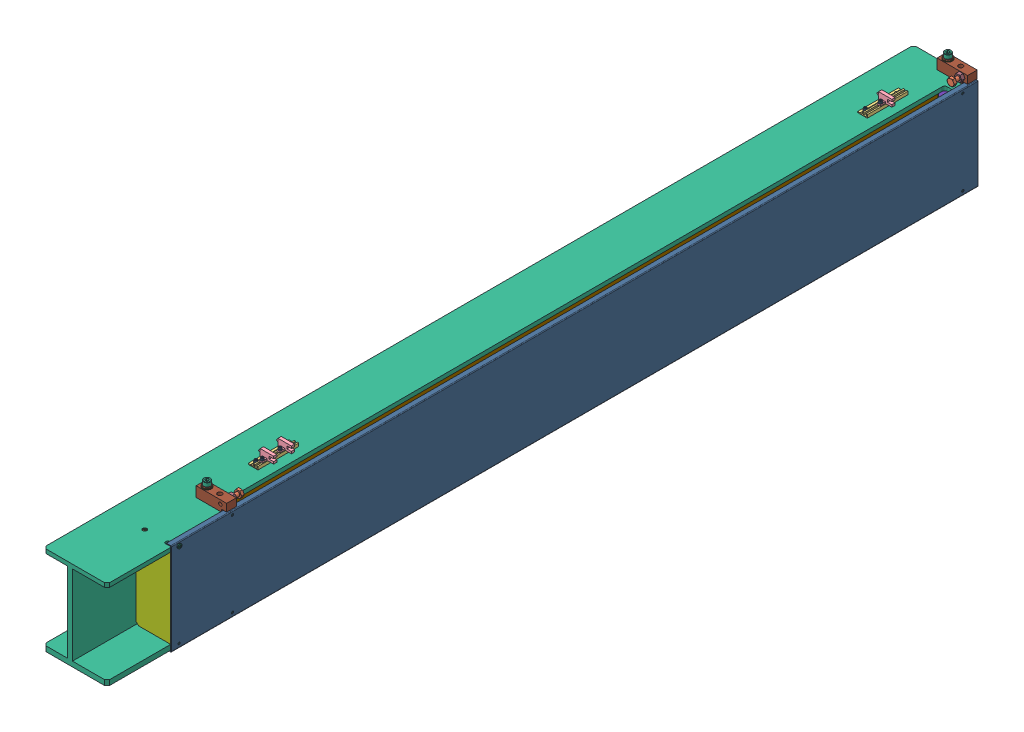
SolidWorks assembly _0227_SA03, configuration Default. Lengths in mm.
Overall size (128.98 209.6 1710.78).
64 component instances, 28 part files, 168 mates.
Components (placement in the parent):
- 0227_003_MS5-10-1: 0227_003_MS5-10 [Default] at (-74.5 -50 -288) x (-1 0 0) z (0 -0.924225 -0.381849) size (10 5.08 5.24)
- 0227_003_MS5-10-2: 0227_003_MS5-10 [Default] at (-74.5 -156 -288) x (-1 0 0) z (0 -0.924225 -0.381849) size (10 5.08 5.24)
- 0227_003_MS5-10-3: 0227_003_MS5-10 [Default] at (-74.5 -50 -1668) x (-1 0 0) z (0 -0.924225 -0.381849) size (10 5.08 5.24)
- 0227_003_MS5-10-4: 0227_003_MS5-10 [Default] at (-74.5 -156 -1668) x (-1 0 0) z (0 -0.924225 -0.381849) size (10 5.08 5.24)
- 0227_010_STRN8-30-1: 0227_010_STRN8-30 [Default] at (-12.5 12.5 -269.5) x (0 0 1) z (0 -1 0) size (35.5 15 13)
- 0227_010_STRN8-30-2: 0227_010_STRN8-30 [Default] at (-12.5 12.5 -1675.5) x (0 0 -1) z (0 -1 0) size (35.5 15 13)
- 0227_011_SENCF3-80-1: 0227_011_SENCF3-80 [Default] at (-46 0 -422.5) x (0 1 0) z (0 0 -1) size (6 19 80)
- 0227_011_SENCF3-80-2: 0227_011_SENCF3-80 [Default] at (-46 0 -1620) x (0 1 0) z (0 0 -1) size (6 19 80)
- 0227_012_FPMT44-1: 0227_012_FPMT44 [Default] at (-60.8 12.7 -361.8) x (0 1 0) z (-1 0 0) size (13.4 26 31.2)
- 0227_012_FPMT44-2: 0227_012_FPMT44 [Default] at (-60.8 12.7 -1576.8) x (0 1 0) z (-1 0 0) size (13.4 26 31.2)
- 0227_012_FPMT44-3: 0227_012_FPMT44 [Default] at (-60.8 12.7 -396.8) x (0 1 0) z (-1 0 0) size (13.4 26 31.2)
- 0227_013_MS6-15-1: 0227_013_MS6-15 [Default] at (-74.5 -50 -195) x (-1 0 0) z (0 -0.594861 -0.803828) size (15 6.1 6.29)
- 0227_013_MS6-15-2: 0227_013_MS6-15 [Default] at (-74.5 -140 -195) x (-1 0 0) z (0 -0.52179 0.853074) size (15 6.1 6.29)
- 0227_201_Base-1: 0227_201_Base [Default] at origin size (125 175 1710)
- 0227_202_Rib-1: 0227_202_Rib [Default] at (-68 -86.5 -125) size (68 157 10)
- 0227_203_Rib-1: 0227_203_Rib [Default] at (-68 -86.5 -1702) size (68 157 8)
- 0227_205_Spacer-1: 0227_205_Spacer [Default] at (-68 -47.5 -260) size (23.5 19 1420)
- 0227_205_Spacer-2: 0227_205_Spacer [Default] at (-68 -153.5 -260) size (23.5 19 1420)
- 0227_207_Cover-1: 0227_207_Cover [Default] at (1.5 3 -125) size (10 181 1585)
- 0227_213_Block-1: 0227_213_Block [Default] at (-60 0 -244.5) size (60 20 19)
- 0227_213_Block-2: 0227_213_Block [Default] at (-60 0 -1700.5) size (60 20 19)
- 0227_309_SCB4-15-1: 0227_309_SCB4-15 [Default] at (-56 -4.5 -130) x (0 -1 0) z (0.5 0 0.866025) size (19 7 7)
- 0227_309_SCB4-15-2: 0227_309_SCB4-15 [Default] at (-56 -170.5 -130) x (0 1 0) z (-0.5 0 0.866025) size (19 7 7)
- 0227_309_SCB4-15-3: 0227_309_SCB4-15 [Default] at (-56 -170.5 -1706) x (0 1 0) z (-0.5 0 0.866025) size (19 7 7)
- 0227_309_SCB4-15-4: 0227_309_SCB4-15 [Default] at (-56 -4.5 -1706) x (0 -1 0) z (0.5 0 0.866025) size (19 7 7)
- 0227_313_SHNJ-M8-1: 0227_313_SHNJ-M8 [Default] at (-12.5 12.5 -260.5) x (0 0 1) z (-0.866025 -0.5 0) size (6.5 15.01 13)
- 0227_313_SHNJ-M8-2: 0227_313_SHNJ-M8 [Default] at (-12.5 12.5 -1684.5) x (0 0 -1) z (0.866025 -0.5 0) size (6.5 15.01 13)
- 0227_314_SHNJ-M3-1: 0227_314_SHNJ-M3 [Default] at (-50.5 2.1 -355.5) x (1 0 0) z (0 -1 0) size (5.5 6.35 2.4)
- 0227_314_SHNJ-M3-2: 0227_314_SHNJ-M3 [Default] at (-50.5 2.1 -390.5) x (1 0 0) z (0 -1 0) size (5.5 6.35 2.4)
- 0227_314_SHNJ-M3-3: 0227_314_SHNJ-M3 [Default] at (-50.5 2.1 -1570.5) x (1 0 0) z (0 -1 0) size (5.5 6.35 2.4)
- 0227_315_BDJS4-8-1: 0227_315_BDJS4-8 [Default] at (1.5 -4 -140) x (-1 0 0) z (0 0 -1) size (10.48 8.3 8.3)
- 0227_317_PWF8-1: 0227_317_PWF8 [Default] at (-48 20.8 -244.5) x (0 -1 0) z (-0.246577 0 0.969123) size (1.6 17 17)
- 0227_317_PWF8-2: 0227_317_PWF8 [Default] at (-48 20.8 -1700.5) x (0 -1 0) z (0 0 1) size (1.6 17 17)
- 0227_318_PWF5-1: 0227_318_PWF5 [Default] at (-78.5 -28 -130) size (1 10 10)
- 0227_319_PWF4-1: 0227_319_PWF4 [Default] at (-78.4 -143 -288) size (0.8 9 9)
- 0227_319_PWF4-2: 0227_319_PWF4 [Default] at (-78.4 -37 -288) size (0.8 9 9)
- 0227_319_PWF4-3: 0227_319_PWF4 [Default] at (-78.4 -28 -1706) size (0.8 9 9)
- 0227_320_PWF3-1: 0227_320_PWF3 [Default] at (-60 2.25 -352.5) x (0 -1 0) z (0 0 1) size (0.5 7 7)
- 0227_320_PWF3-2: 0227_320_PWF3 [Default] at (-50.5 9.25 -355.5) x (0 -1 0) z (0 0 1) size (0.5 7 7)
- 0227_320_PWF3-3: 0227_320_PWF3 [Default] at (-60 2.25 -1550) x (0 -1 0) z (0 0 1) size (0.5 7 7)
- 0227_320_PWF3-4: 0227_320_PWF3 [Default] at (-50.5 9.25 -390.5) x (0 -1 0) z (0 0 1) size (0.5 7 7)
- 0227_320_PWF3-5: 0227_320_PWF3 [Default] at (-50.5 9.25 -1570.5) x (0 -1 0) z (0 0 1) size (0.5 7 7)
- 0227_321_SLW8-1: 0227_321_SLW8 [Default] at (-48 22.6 -244.5) x (0 -1 0) z (1 0 0) size (2 15.4 15.4)
- 0227_321_SLW8-2: 0227_321_SLW8 [Default] at (-48 22.6 -1700.5) x (0 -1 0) z (1 0 0) size (2 15.4 15.4)
- 0227_322_SLW5-1: 0227_322_SLW5 [Default] at (-79.65 -28 -130) x (1 0 0) z (0 1 0) size (1.3 9.2 9.2)
- 0227_323_SLW4-1: 0227_323_SLW4 [Default] at (-79.3 -143 -288) x (1 0 0) z (0 -1 0) size (1 7.6 7.6)
- 0227_323_SLW4-2: 0227_323_SLW4 [Default] at (-79.3 -37 -288) x (1 0 0) z (0 -1 0) size (1 7.6 7.6)
- 0227_323_SLW4-3: 0227_323_SLW4 [Default] at (-79.3 -28 -1706) x (1 0 0) z (0 -1 0) size (1 7.6 7.6)
- 0227_324_SLW3-1: 0227_324_SLW3 [Default] at (-60 2.85 -352.5) x (0 -1 0) z (1 0 0) size (0.7 5.9 5.9)
- 0227_324_SLW3-2: 0227_324_SLW3 [Default] at (-50.5 9.85 -355.5) x (0 -1 0) z (0.999786 0 0.020691) size (0.7 5.9 5.9)
- 0227_324_SLW3-3: 0227_324_SLW3 [Default] at (-60 2.85 -1550) x (0 -1 0) z (1 0 0) size (0.7 5.9 5.9)
- 0227_324_SLW3-4: 0227_324_SLW3 [Default] at (-50.5 9.85 -390.5) x (0 -1 0) z (1 0 0) size (0.7 5.9 5.9)
- 0227_324_SLW3-5: 0227_324_SLW3 [Default] at (-50.5 9.85 -1570.5) x (0 -1 0) z (1 0 0) size (0.7 5.9 5.9)
- 0227_301_SCB8-30-1: 0227_301_SCB8-30 [Default] at (-48 23.6 -244.5) x (0 -1 0) z (-0.5 0 -0.866025) size (38 13 13)
- 0227_301_SCB8-30-2: 0227_301_SCB8-30 [Default] at (-48 23.6 -1700.5) x (0 -1 0) z (-0.5 0 -0.866025) size (38 13 13)
- 0227_304_SCB5-20-1: 0227_304_SCB5-20 [Default] at (-80.3 -28 -130) x (1 0 0) z (0 -0.5 0.866025) size (25 8.5 8.5)
- 0227_308_SCB4-16-1: 0227_308_SCB4-16 [Default] at (-79.8 -143 -288) x (1 0 0) z (0 0.5 0.866025) size (20 7 7)
- 0227_307_SCB4-20-1: 0227_307_SCB4-20 [Default] at (-79.8 -37 -288) x (1 0 0) z (0 0.5 0.866025) size (24 7 7)
- 0227_307_SCB4-20-2: 0227_307_SCB4-20 [Default] at (-79.8 -28 -1706) x (1 0 0) z (0 0.5 0.866025) size (24 7 7)
- 0227_311_SCB3-8-1: 0227_311_SCB3-8 [Default] at (-60 3.2 -352.5) x (0 -1 0) z (-0.5 0 0.866025) size (11 5.5 5.5)
- 0227_311_SCB3-8-2: 0227_311_SCB3-8 [Default] at (-50.5 10.2 -355.5) x (0 -1 0) z (-0.5 0 0.866025) size (11 5.5 5.5)
- 0227_311_SCB3-8-3: 0227_311_SCB3-8 [Default] at (-60 3.2 -1550) x (0 -1 0) z (-0.5 0 0.866025) size (11 5.5 5.5)
- 0227_311_SCB3-8-4: 0227_311_SCB3-8 [Default] at (-50.5 10.2 -390.5) x (0 -1 0) z (-0.5 0 0.866025) size (11 5.5 5.5)
- 0227_311_SCB3-8-5: 0227_311_SCB3-8 [Default] at (-50.5 10.2 -1570.5) x (0 -1 0) z (-0.5 0 0.866025) size (11 5.5 5.5)
Mates (geometry in assembly coordinates):
- Concentric1: concentric aligned: cylinder of 0227_201_Base-1 through (-78 -28 -130) axis (-1 0 0) radius 2.75; cylinder of 0227_202_Rib-1 through (-68 -28 -130) axis (-1 0 0) radius 2.1
- Concentric2: concentric aligned: cylinder of 0227_201_Base-1 through (-78 -145 -130) axis (-1 0 0) radius 2.75; cylinder of 0227_202_Rib-1 through (-68 -145 -130) axis (-1 0 0) radius 2.1
- Coincident1: coincident anti-aligned: plane of 0227_201_Base-1 through (-68 -165 0) normal (1 0 0); plane of 0227_202_Rib-1 through (-68 -165 -135) normal (-1 0 0)
- Concentric3: concentric aligned: cylinder of 0227_201_Base-1 through (-78 -145 -1706) axis (-1 0 0) radius 2.25; cylinder of 0227_203_Rib-1 through (-68 -145 -1706) axis (-1 0 0) radius 1.65
- Concentric4: concentric aligned: cylinder of 0227_201_Base-1 through (-78 -86.5 -1706) axis (-1 0 0) radius 2.25; cylinder of 0227_203_Rib-1 through (-68 -86.5 -1706) axis (-1 0 0) radius 1.65
- Coincident2: coincident anti-aligned: plane of 0227_201_Base-1 through (-68 -165 0) normal (1 0 0); plane of 0227_203_Rib-1 through (-68 -165 -1710) normal (-1 0 0)
- Concentric5: concentric anti-aligned: cylinder of 0227_201_Base-1 through (-68 -37 -288) axis (1 0 0) radius 2.25; cylinder of 0227_205_Spacer-1 through (-68 -37 -288) axis (-1 0 0) radius 1.65
- Concentric6: concentric anti-aligned: cylinder of 0227_201_Base-1 through (-68 -37 -468) axis (1 0 0) radius 2.25; cylinder of 0227_205_Spacer-1 through (-68 -37 -468) axis (-1 0 0) radius 1.65
- Concentric7: concentric anti-aligned: cylinder of 0227_201_Base-1 through (-68 -37 -1668) axis (1 0 0) radius 2.25; cylinder of 0227_205_Spacer-1 through (-68 -37 -1668) axis (-1 0 0) radius 1.65
- Concentric8: concentric anti-aligned: cylinder of 0227_201_Base-1 through (-68 -143 -288) axis (1 0 0) radius 2.25; cylinder of 0227_205_Spacer-2 through (-68 -143 -288) axis (-1 0 0) radius 1.65
- Concentric9: concentric anti-aligned: cylinder of 0227_201_Base-1 through (-68 -143 -348) axis (1 0 0) radius 2.25; cylinder of 0227_205_Spacer-2 through (-68 -143 -348) axis (-1 0 0) radius 1.65
- Coincident3: coincident anti-aligned: plane of 0227_201_Base-1 through (-68 -165 0) normal (1 0 0); plane of 0227_205_Spacer-1 through (-68 -28.5 -260) normal (-1 0 0)
- Coincident4: coincident anti-aligned: plane of 0227_201_Base-1 through (-68 -165 0) normal (1 0 0); plane of 0227_205_Spacer-2 through (-68 -134.5 -260) normal (-1 0 0)
- Concentric10: concentric aligned: cylinder of 0227_201_Base-1 through (0 -4 -140) axis (1 0 0) radius 1.65; cylinder of 0227_207_Cover-1 through (1.5 -4 -140) axis (1 0 0) radius 2.25
- Concentric11: concentric aligned: cylinder of 0227_201_Base-1 through (0 -4 -245) axis (1 0 0) radius 1.65; cylinder of 0227_207_Cover-1 through (1.5 -4 -245) axis (1 0 0) radius 2.25
- Coincident6: coincident anti-aligned: plane of 0227_201_Base-1 through (0 -8 0) normal (1 0 0); plane of 0227_207_Cover-1 through (0 -176.5 -1710) normal (-1 0 0)
- Concentric12: concentric aligned: cylinder of 0227_201_Base-1 through (-48 0 -244.5) axis (0 1 0) radius 3.4; cylinder of 0227_213_Block-1 through (-48 20 -244.5) axis (0 1 0) radius 4.5
- Concentric13: concentric aligned: cylinder of 0227_201_Base-1 through (-23 0 -244.5) axis (0 1 0) radius 3.4; cylinder of 0227_213_Block-1 through (-23 20 -244.5) axis (0 1 0) radius 4.5
- Coincident7: coincident anti-aligned: plane of 0227_201_Base-1 through (-125 0 -1710) normal (0 1 0); plane of 0227_213_Block-1 through (-60 0 -254) normal (0 -1 0)
- Concentric14: concentric aligned: cylinder of 0227_201_Base-1 through (-48 0 -1700.5) axis (0 1 0) radius 3.4; cylinder of 0227_213_Block-2 through (-48 20 -1700.5) axis (0 1 0) radius 4.5
- Concentric15: concentric aligned: cylinder of 0227_201_Base-1 through (-23 0 -1700.5) axis (0 1 0) radius 3.4; cylinder of 0227_213_Block-2 through (-23 20 -1700.5) axis (0 1 0) radius 4.5
- Coincident8: coincident anti-aligned: plane of 0227_201_Base-1 through (-125 0 -1710) normal (0 1 0); plane of 0227_213_Block-2 through (-60 0 -1710) normal (0 -1 0)
- Concentric16: concentric aligned: cylinder of 0227_213_Block-1 through (-12.5 12.5 -235) axis (0 0 1) radius 3.4; cylinder of 0227_010_STRN8-30-1 through (-12.5 12.5 -254.6835) axis (0 0 1) radius 4
- Distance1: distance = 15.5 mm anti-aligned: plane of 0227_010_STRN8-30-1 through (-18.45 12.5 -269.5) normal (0 0 1); plane of 0227_213_Block-1 through (-60 20 -254) normal (0 0 -1)
- Parallel1: parallel aligned: plane of 0227_213_Block-1 through (-60 20 -254) normal (0 1 0); plane of 0227_010_STRN8-30-1 through (-16.2528 19 -269.5) normal (0 1 0)
- Concentric17: concentric anti-aligned: cylinder of 0227_213_Block-2 through (-12.5 12.5 -1691) axis (0 0 1) radius 3.4; cylinder of 0227_010_STRN8-30-2 through (-12.5 12.5 -1690.3165) axis (0 0 -1) radius 4
- Distance2: distance = 15.5 mm anti-aligned: plane of 0227_213_Block-2 through (-60 20 -1691) normal (0 0 1); plane of 0227_010_STRN8-30-2 through (-6.55 12.5 -1675.5) normal (0 0 -1)
- Parallel2: parallel aligned: plane of 0227_213_Block-2 through (-60 20 -1710) normal (0 1 0); plane of 0227_010_STRN8-30-2 through (-8.7472 19 -1675.5) normal (0 1 0)
- Concentric18: concentric anti-aligned: cylinder of 0227_201_Base-1 through (-60 0 -352.5) axis (0 1 0) radius 1.25; cylinder of 0227_011_SENCF3-80-1 through (-60 0 -352.5) axis (0 -1 0) radius 1.75
- Concentric19: concentric anti-aligned: cylinder of 0227_201_Base-1 through (-60 0 -412.5) axis (0 1 0) radius 1.25; cylinder of 0227_011_SENCF3-80-1 through (-60 0 -412.5) axis (0 -1 0) radius 1.75
- Coincident13: coincident anti-aligned: plane of 0227_201_Base-1 through (-125 0 -1710) normal (0 1 0); plane of 0227_011_SENCF3-80-1 through (-46 0 -342.5) normal (0 -1 0)
- Concentric20: concentric anti-aligned: cylinder of 0227_201_Base-1 through (-60 0 -1550) axis (0 1 0) radius 1.25; cylinder of 0227_011_SENCF3-80-2 through (-60 0 -1550) axis (0 -1 0) radius 1.75
- Concentric21: concentric anti-aligned: cylinder of 0227_201_Base-1 through (-60 0 -1610) axis (0 1 0) radius 1.25; cylinder of 0227_011_SENCF3-80-2 through (-60 0 -1610) axis (0 -1 0) radius 1.75
- Coincident14: coincident anti-aligned: plane of 0227_201_Base-1 through (-125 0 -1710) normal (0 1 0); plane of 0227_011_SENCF3-80-2 through (-46 0 -1540) normal (0 -1 0)
- Width1: width aligned: plane of 0227_012_FPMT44-1 through (-47.4 9 -378) normal (1 0 0); plane of 0227_012_FPMT44-1 through (-53.6 9 -378) normal (-1 0 0); plane of 0227_011_SENCF3-80-1 through (-46 6 -342.5) normal (1 0 0); plane of 0227_011_SENCF3-80-1 through (-55 2 -342.5) normal (-1 0 0)
- Coincident15: coincident anti-aligned: plane of 0227_011_SENCF3-80-1 through (-48.8 6 -342.5) normal (0 1 0); plane of 0227_012_FPMT44-1 through (-60.8 6 -368.2) normal (0 -1 0)
- Distance3: distance = 9.5 mm aligned: plane of 0227_012_FPMT44-1 through (-47.4 9 -352) normal (0 0 1); plane of 0227_011_SENCF3-80-1 through (-48.8 6 -342.5) normal (0 0 1)
- Coincident17: coincident aligned: plane of 0227_012_FPMT44-1 through (-47.4 9 -378) normal (1 0 0); plane of 0227_012_FPMT44-2 through (-47.4 9 -1593) normal (1 0 0)
- Coincident18: coincident anti-aligned: plane of 0227_011_SENCF3-80-2 through (-48.8 6 -1540) normal (0 1 0); plane of 0227_012_FPMT44-2 through (-60.8 6 -1583.2) normal (0 -1 0)
- Distance4: distance = 27 mm aligned: plane of 0227_012_FPMT44-2 through (-47.4 9 -1567) normal (0 0 1); plane of 0227_011_SENCF3-80-2 through (-48.8 6 -1540) normal (0 0 1)
- Coincident20: coincident aligned: plane of 0227_012_FPMT44-1 through (-47.4 9 -378) normal (1 0 0); plane of 0227_012_FPMT44-3 through (-47.4 9 -413) normal (1 0 0)
- Coincident21: coincident anti-aligned: plane of 0227_011_SENCF3-80-1 through (-48.8 6 -342.5) normal (0 1 0); plane of 0227_012_FPMT44-3 through (-60.8 6 -403.2) normal (0 -1 0)
- Distance5: distance = 9 mm anti-aligned: plane of 0227_012_FPMT44-1 through (-47.4 9 -378) normal (0 0 -1); plane of 0227_012_FPMT44-3 through (-47.4 9 -387) normal (0 0 1)
- Concentric22: concentric anti-aligned: cylinder of 0227_213_Block-1 through (-48 20 -244.5) axis (0 1 0) radius 4.5; cylinder of 0227_317_PWF8-1 through (-48 20.8 -244.5) axis (0 -1 0) radius 4.2
- Coincident23: coincident anti-aligned: plane of 0227_213_Block-1 through (-60 20 -254) normal (0 1 0); plane of 0227_317_PWF8-1 through (-41.8461 20 -242.9342) normal (0 -1 0)
- Concentric23: concentric aligned: cylinder of 0227_213_Block-1 through (-48 20 -244.5) axis (0 1 0) radius 4.5; cylinder of 0227_301_SCB8-30-1 through (-48 -6.4 -244.5) axis (0 1 0) radius 4
- Parallel3: parallel aligned: plane of 0227_213_Block-1 through (0 0 -254) normal (1 0 0); plane of 0227_301_SCB8-30-1 through (-51 27.6 -242.7679) normal (1 0 0)
- Concentric24: concentric anti-aligned: cylinder of 0227_301_SCB8-30-2 through (-48 -6.4 -1700.5) axis (0 1 0) radius 4; cylinder of 0227_317_PWF8-2 through (-48 20.8 -1700.5) axis (0 -1 0) radius 4.2
- Concentric25: concentric aligned: cylinder of 0227_213_Block-2 through (-48 20 -1700.5) axis (0 1 0) radius 4.5; cylinder of 0227_301_SCB8-30-2 through (-48 -6.4 -1700.5) axis (0 1 0) radius 4
- Coincident27: coincident anti-aligned: plane of 0227_213_Block-2 through (-60 20 -1710) normal (0 1 0); plane of 0227_317_PWF8-2 through (-41.65 20 -1700.5) normal (0 -1 0)
- Concentric26: concentric anti-aligned: cylinder of 0227_304_SCB5-20-1 through (-60.3 -28 -130) axis (-1 0 0) radius 2.5; cylinder of 0227_318_PWF5-1 through (-78.5 -28 -130) axis (1 0 0) radius 2.65
- Concentric27: concentric anti-aligned: cylinder of 0227_304_SCB5-20-1 through (-60.3 -28 -130) axis (-1 0 0) radius 2.5; cylinder of 0227_322_SLW5-1 through (-79.65 -28 -130) axis (1 0 0) radius 2.55
- Coincident28: coincident anti-aligned: plane of 0227_304_SCB5-20-1 through (-80.3 -24.3194 -127.875) normal (1 0 0); plane of 0227_322_SLW5-1 through (-80.3 -28 -133.575) normal (-1 0 0)
- Coincident29: coincident anti-aligned: plane of 0227_322_SLW5-1 through (-79 -28 -133.575) normal (1 0 0); plane of 0227_318_PWF5-1 through (-79 -24.175 -130) normal (-1 0 0)
- Concentric28: concentric aligned: cylinder of 0227_201_Base-1 through (-78 -28 -130) axis (-1 0 0) radius 2.75; cylinder of 0227_304_SCB5-20-1 through (-60.3 -28 -130) axis (-1 0 0) radius 2.5
- Coincident30: coincident anti-aligned: plane of 0227_201_Base-1 through (-78 -165 0) normal (-1 0 0); plane of 0227_318_PWF5-1 through (-78 -24.175 -130) normal (1 0 0)
- Parallel4: parallel anti-aligned: plane of 0227_201_Base-1 through (-125 0 -1710) normal (0 1 0); plane of 0227_304_SCB5-20-1 through (-82.8 -26 -131.1547) normal (0 -1 0)
- Perpendicular1: perpendicular: plane of 0227_201_Base-1 through (-125 0 -1710) normal (0 1 0); plane of 0227_322_SLW5-1 through (-79.65 -28 -130) normal (0 0 -1)
- Concentric29: concentric anti-aligned: cylinder of 0227_308_SCB4-16-1 through (-63.8 -143 -288) axis (-1 0 0) radius 2; cylinder of 0227_323_SLW4-1 through (-79.3 -143 -288) axis (1 0 0) radius 2.05
- Concentric30: concentric anti-aligned: cylinder of 0227_308_SCB4-16-1 through (-63.8 -143 -288) axis (-1 0 0) radius 2; cylinder of 0227_319_PWF4-1 through (-78.4 -143 -288) axis (1 0 0) radius 2.15
- Coincident33: coincident anti-aligned: plane of 0227_319_PWF4-1 through (-78.8 -139.675 -288) normal (-1 0 0); plane of 0227_323_SLW4-1 through (-78.8 -143 -285.075) normal (1 0 0)
- Coincident34: coincident anti-aligned: plane of 0227_308_SCB4-16-1 through (-79.8 -139.9689 -289.75) normal (1 0 0); plane of 0227_323_SLW4-1 through (-79.8 -143 -285.075) normal (-1 0 0)
- Concentric31: concentric anti-aligned: cylinder of 0227_308_SCB4-16-1 through (-63.8 -143 -288) axis (-1 0 0) radius 2; cylinder of 0227_201_Base-1 through (-68 -143 -288) axis (1 0 0) radius 2.25
- Coincident35: coincident anti-aligned: plane of 0227_201_Base-1 through (-78 -165 0) normal (-1 0 0); plane of 0227_319_PWF4-1 through (-78 -139.675 -288) normal (1 0 0)
- Parallel5: parallel aligned: plane of 0227_201_Base-1 through (-125 -175 -1710) normal (0 -1 0); plane of 0227_308_SCB4-16-1 through (-81.8 -141.5 -288.866) normal (0 -1 0)
- Parallel6: parallel aligned: plane of 0227_201_Base-1 through (-125 -175 -1710) normal (0 -1 0); plane of 0227_323_SLW4-1 through (-79.3 -143 -288) normal (0 -1 0)
- Concentric32: concentric anti-aligned: cylinder of 0227_307_SCB4-20-1 through (-59.8 -37 -288) axis (-1 0 0) radius 2; cylinder of 0227_323_SLW4-2 through (-79.3 -37 -288) axis (1 0 0) radius 2.05
- Concentric33: concentric anti-aligned: cylinder of 0227_307_SCB4-20-1 through (-59.8 -37 -288) axis (-1 0 0) radius 2; cylinder of 0227_319_PWF4-2 through (-78.4 -37 -288) axis (1 0 0) radius 2.15
- Coincident38: coincident anti-aligned: plane of 0227_323_SLW4-2 through (-78.8 -37 -285.075) normal (1 0 0); plane of 0227_319_PWF4-2 through (-78.8 -33.675 -288) normal (-1 0 0)
- Coincident39: coincident anti-aligned: plane of 0227_307_SCB4-20-1 through (-79.8 -33.9689 -289.75) normal (1 0 0); plane of 0227_323_SLW4-2 through (-79.8 -37 -285.075) normal (-1 0 0)
- Concentric34: concentric anti-aligned: cylinder of 0227_201_Base-1 through (-68 -37 -288) axis (1 0 0) radius 2.25; cylinder of 0227_307_SCB4-20-1 through (-59.8 -37 -288) axis (-1 0 0) radius 2
- Coincident40: coincident anti-aligned: plane of 0227_201_Base-1 through (-78 -165 0) normal (-1 0 0); plane of 0227_319_PWF4-2 through (-78 -33.675 -288) normal (1 0 0)
- Parallel7: parallel aligned: plane of 0227_201_Base-1 through (-125 -8 -1710) normal (0 -1 0); plane of 0227_307_SCB4-20-1 through (-81.8 -35.5 -288.866) normal (0 -1 0)
- Concentric35: concentric anti-aligned: cylinder of 0227_307_SCB4-20-2 through (-59.8 -28 -1706) axis (-1 0 0) radius 2; cylinder of 0227_323_SLW4-3 through (-79.3 -28 -1706) axis (1 0 0) radius 2.05
- Concentric36: concentric anti-aligned: cylinder of 0227_307_SCB4-20-2 through (-59.8 -28 -1706) axis (-1 0 0) radius 2; cylinder of 0227_319_PWF4-3 through (-78.4 -28 -1706) axis (1 0 0) radius 2.15
- Coincident42: coincident anti-aligned: plane of 0227_323_SLW4-3 through (-78.8 -28 -1703.075) normal (1 0 0); plane of 0227_319_PWF4-3 through (-78.8 -24.675 -1706) normal (-1 0 0)
- Coincident43: coincident anti-aligned: plane of 0227_307_SCB4-20-2 through (-79.8 -24.9689 -1707.75) normal (1 0 0); plane of 0227_323_SLW4-3 through (-79.8 -28 -1703.075) normal (-1 0 0)
- Concentric37: concentric aligned: cylinder of 0227_201_Base-1 through (-78 -28 -1706) axis (-1 0 0) radius 2.25; cylinder of 0227_307_SCB4-20-2 through (-59.8 -28 -1706) axis (-1 0 0) radius 2
- Coincident44: coincident anti-aligned: plane of 0227_201_Base-1 through (-78 -165 0) normal (-1 0 0); plane of 0227_319_PWF4-3 through (-78 -24.675 -1706) normal (1 0 0)
- Parallel8: parallel aligned: plane of 0227_201_Base-1 through (-125 -8 -1710) normal (0 -1 0); plane of 0227_307_SCB4-20-2 through (-81.8 -26.5 -1706.866) normal (0 -1 0)
- Parallel9: parallel anti-aligned: plane of 0227_201_Base-1 through (-125 -8 -1710) normal (0 0 -1); plane of 0227_323_SLW4-3 through (-79.3 -28 -1706) normal (0 0 1)
- Concentric39: concentric anti-aligned: cylinder of 0227_201_Base-1 through (-56 0 -130) axis (0 1 0) radius 2.25; cylinder of 0227_309_SCB4-15-1 through (-56 -11.7853 -130) axis (0 -1 0) radius 2
- Coincident45: coincident anti-aligned: plane of 0227_201_Base-1 through (-53.75 -4.5 -130) normal (0 1 0); plane of 0227_309_SCB4-15-1 through (-53.6184 -4.5 -131.375) normal (0 -1 0)
- Parallel10: parallel aligned: plane of 0227_201_Base-1 through (0 -8 0) normal (1 0 0); plane of 0227_309_SCB4-15-1 through (-57.5 -0.5 -130.866) normal (1 0 0)
- Concentric41: concentric anti-aligned: cylinder of 0227_201_Base-1 through (-56 -175 -130) axis (0 -1 0) radius 4; cylinder of 0227_309_SCB4-15-2 through (-56 -163.2147 -130) axis (0 1 0) radius 2
- Coincident47: coincident anti-aligned: plane of 0227_201_Base-1 through (-53.75 -170.5 -130) normal (0 -1 0); plane of 0227_309_SCB4-15-2 through (-58.3816 -170.5 -131.375) normal (0 1 0)
- Parallel11: parallel aligned: plane of 0227_201_Base-1 through (0 -175 0) normal (1 0 0); plane of 0227_309_SCB4-15-2 through (-57.5 -174.5 -129.134) normal (1 0 0)
- Concentric42: concentric anti-aligned: cylinder of 0227_309_SCB4-15-3 through (-56 -163.2147 -1706) axis (0 1 0) radius 2; cylinder of 0227_201_Base-1 through (-56 -170.5 -1706) axis (0 -1 0) radius 2.25
- Coincident49: coincident anti-aligned: plane of 0227_201_Base-1 through (-56 -170.5 -1706) normal (0 -1 0); plane of 0227_309_SCB4-15-3 through (-58.3816 -170.5 -1707.375) normal (0 1 0)
- Concentric43: concentric anti-aligned: cylinder of 0227_201_Base-1 through (-56 -4.5 -1706) axis (0 1 0) radius 2.25; cylinder of 0227_309_SCB4-15-4 through (-56 -11.7853 -1706) axis (0 -1 0) radius 2
- Coincident51: coincident anti-aligned: plane of 0227_201_Base-1 through (-56 -4.5 -1706) normal (0 1 0); plane of 0227_309_SCB4-15-4 through (-53.6184 -4.5 -1707.375) normal (0 -1 0)
- Parallel12: parallel aligned: plane of 0227_213_Block-2 through (0 0 -1710) normal (1 0 0); plane of 0227_301_SCB8-30-2 through (-51 27.6 -1698.7679) normal (1 0 0)
- Concentric44: concentric anti-aligned: cylinder of 0227_010_STRN8-30-1 through (-12.5 12.5 -254.6835) axis (0 0 1) radius 4; cylinder of 0227_313_SHNJ-M8-1 through (-12.5 12.5 -254) axis (0 0 -1) radius 3.3235
- Coincident53: coincident anti-aligned: plane of 0227_213_Block-1 through (-60 20 -254) normal (0 0 -1); plane of 0227_313_SHNJ-M8-1 through (-17.05 20.3808 -254) normal (0 0 1)
- Parallel13: parallel aligned: plane of 0227_213_Block-1 through (-60 20 -254) normal (0 1 0); plane of 0227_313_SHNJ-M8-1 through (-8.7472 19 -252) normal (0 1 0)
- Concentric45: concentric anti-aligned: cylinder of 0227_010_STRN8-30-2 through (-12.5 12.5 -1690.3165) axis (0 0 -1) radius 4; cylinder of 0227_313_SHNJ-M8-2 through (-12.5 12.5 -1691) axis (0 0 1) radius 3.3235
- Coincident55: coincident anti-aligned: plane of 0227_213_Block-2 through (-60 20 -1691) normal (0 0 1); plane of 0227_313_SHNJ-M8-2 through (-7.95 20.3808 -1691) normal (0 0 -1)
- Parallel14: parallel aligned: plane of 0227_213_Block-2 through (-60 20 -1710) normal (0 1 0); plane of 0227_313_SHNJ-M8-2 through (-16.2528 19 -1693) normal (0 1 0)
- Concentric46: concentric anti-aligned: cylinder of 0227_201_Base-1 through (0 -4 -140) axis (1 0 0) radius 1.65; cylinder of 0227_315_BDJS4-8-1 through (-3.2 -4 -140) axis (-1 0 0) radius 2
- Coincident57: coincident anti-aligned: plane of 0227_207_Cover-1 through (1.5 -178 -1710) normal (1 0 0); plane of 0227_315_BDJS4-8-1 through (1.5 -0.9324 -140) normal (-1 0 0)
- Parallel15: parallel anti-aligned: plane of 0227_201_Base-1 through (-125 0 -1710) normal (0 1 0); plane of 0227_315_BDJS4-8-1 through (4 -1.85 -140.5533) normal (0 -1 0)
- Coincident59: coincident anti-aligned: plane of 0227_011_SENCF3-80-1 through (-52.2 4.5 -342.5) normal (0 -1 0); plane of 0227_314_SHNJ-M3-1 through (-56 4.5 -355.5) normal (0 1 0)
- Width2: width aligned: plane of 0227_314_SHNJ-M3-1 through (-47.75 4.5 -353.9123) normal (1 0 0); plane of 0227_314_SHNJ-M3-1 through (-53.25 4.5 -353.9123) normal (-1 0 0); plane of 0227_011_SENCF3-80-1 through (-46 6 -342.5) normal (1 0 0); plane of 0227_011_SENCF3-80-1 through (-55 2 -342.5) normal (-1 0 0)
- Coincident60: coincident aligned: plane of 0227_314_SHNJ-M3-1 through (-56 4.5 -355.5) normal (0 1 0); plane of 0227_314_SHNJ-M3-2 through (-56 4.5 -390.5) normal (0 1 0)
- Coincident61: coincident aligned: plane of 0227_314_SHNJ-M3-1 through (-47.75 4.5 -353.9123) normal (1 0 0); plane of 0227_314_SHNJ-M3-3 through (-47.75 4.5 -1568.9123) normal (1 0 0)
- Coincident62: coincident aligned: plane of 0227_314_SHNJ-M3-1 through (-56 4.5 -355.5) normal (0 1 0); plane of 0227_314_SHNJ-M3-3 through (-56 4.5 -1570.5) normal (0 1 0)
- Coincident63: coincident aligned: plane of 0227_314_SHNJ-M3-1 through (-47.75 4.5 -353.9123) normal (1 0 0); plane of 0227_314_SHNJ-M3-2 through (-47.75 4.5 -388.9123) normal (1 0 0)
- Concentric471: concentric anti-aligned: cylinder of 0227_011_SENCF3-80-1 through (-60 0 -352.5) axis (0 -1 0) radius 1.75; cylinder of 0227_311_SCB3-8-1 through (-60 -4.8 -352.5) axis (0 1 0) radius 1.5
- Symmetric1: symmetric aligned: cylinder of 0227_012_FPMT44-1 through (-50.5 6 -354.95) axis (0 1 0) radius 1.6; cylinder of 0227_012_FPMT44-1 through (-50.5 6 -356.05) axis (0 1 0) radius 1.6; plane of 0227_314_SHNJ-M3-1 through (-50.5 2.1 -355.5) normal (0 0 1)
- Concentric48: concentric aligned: cylinder of 0227_320_PWF3-1 through (-60 2.25 -352.5) axis (0 -1 0) radius 1.6; cylinder of 0227_324_SLW3-1 through (-60 2.85 -352.5) axis (0 -1 0) radius 1.55
- Coincident65: coincident anti-aligned: plane of 0227_320_PWF3-1 through (-57.45 2.5 -352.5) normal (0 1 0); plane of 0227_324_SLW3-1 through (-60 2.5 -354.75) normal (0 -1 0)
- Concentric49: concentric anti-aligned: cylinder of 0227_311_SCB3-8-1 through (-60 -4.8 -352.5) axis (0 1 0) radius 1.5; cylinder of 0227_324_SLW3-1 through (-60 2.85 -352.5) axis (0 -1 0) radius 1.55
- Coincident66: coincident anti-aligned: plane of 0227_311_SCB3-8-1 through (-57.6184 3.2 -351.125) normal (0 -1 0); plane of 0227_324_SLW3-1 through (-60 3.2 -354.75) normal (0 1 0)
- Coincident67: coincident anti-aligned: plane of 0227_011_SENCF3-80-1 through (-65 2 -342.5) normal (0 1 0); plane of 0227_320_PWF3-1 through (-57.45 2 -352.5) normal (0 -1 0)
- Parallel16: parallel aligned: plane of 0227_011_SENCF3-80-1 through (-46 6 -342.5) normal (1 0 0); plane of 0227_311_SCB3-8-1 through (-61.25 4.7 -351.7783) normal (1 0 0)
- Parallel17: parallel aligned: plane of 0227_011_SENCF3-80-1 through (-46 6 -342.5) normal (1 0 0); plane of 0227_324_SLW3-1 through (-60 2.85 -352.5) normal (1 0 0)
- Concentric50: concentric anti-aligned: cylinder of 0227_311_SCB3-8-2 through (-50.5 2.2 -355.5) axis (0 1 0) radius 1.5; cylinder of 0227_320_PWF3-2 through (-50.5 9.25 -355.5) axis (0 -1 0) radius 1.6
- Concentric51: concentric anti-aligned: cylinder of 0227_311_SCB3-8-2 through (-50.5 2.2 -355.5) axis (0 1 0) radius 1.5; cylinder of 0227_324_SLW3-2 through (-50.5 9.85 -355.5) axis (0 -1 0) radius 1.55
- Coincident70: coincident anti-aligned: plane of 0227_320_PWF3-2 through (-47.95 9.5 -355.5) normal (0 1 0); plane of 0227_324_SLW3-2 through (-50.4534 9.5 -357.7495) normal (0 -1 0)
- Coincident71: coincident anti-aligned: plane of 0227_311_SCB3-8-2 through (-48.1184 10.2 -354.125) normal (0 -1 0); plane of 0227_324_SLW3-2 through (-50.4534 10.2 -357.7495) normal (0 1 0)
- Concentric52: concentric anti-aligned: cylinder of 0227_314_SHNJ-M3-1 through (-50.5 4.5 -355.5) axis (0 -1 0) radius 1.25; cylinder of 0227_311_SCB3-8-2 through (-50.5 2.2 -355.5) axis (0 1 0) radius 1.5
- Coincident72: coincident anti-aligned: plane of 0227_012_FPMT44-1 through (-47.4 9 -352) normal (0 1 0); plane of 0227_320_PWF3-2 through (-47.95 9 -355.5) normal (0 -1 0)
- Parallel18: parallel aligned: plane of 0227_012_FPMT44-1 through (-47.4 9 -378) normal (1 0 0); plane of 0227_311_SCB3-8-2 through (-51.75 11.7 -354.7783) normal (1 0 0)
- Symmetric2: symmetric aligned: cylinder of 0227_012_FPMT44-3 through (-50.5 6 -389.95) axis (0 1 0) radius 1.6; cylinder of 0227_012_FPMT44-3 through (-50.5 6 -391.05) axis (0 1 0) radius 1.6; plane of 0227_314_SHNJ-M3-2 through (-50.5 2.1 -390.5) normal (0 0 1)
- Concentric53: concentric anti-aligned: cylinder of 0227_311_SCB3-8-3 through (-60 -4.8 -1550) axis (0 1 0) radius 1.5; cylinder of 0227_320_PWF3-3 through (-60 2.25 -1550) axis (0 -1 0) radius 1.6
- Concentric54: concentric aligned: cylinder of 0227_324_SLW3-3 through (-60 2.85 -1550) axis (0 -1 0) radius 1.55; cylinder of 0227_320_PWF3-3 through (-60 2.25 -1550) axis (0 -1 0) radius 1.6
- Coincident74: coincident anti-aligned: plane of 0227_324_SLW3-3 through (-60 2.5 -1552.25) normal (0 -1 0); plane of 0227_320_PWF3-3 through (-57.45 2.5 -1550) normal (0 1 0)
- Coincident75: coincident anti-aligned: plane of 0227_311_SCB3-8-3 through (-57.6184 3.2 -1548.625) normal (0 -1 0); plane of 0227_324_SLW3-3 through (-60 3.2 -1552.25) normal (0 1 0)
- Concentric55: concentric anti-aligned: cylinder of 0227_311_SCB3-8-4 through (-50.5 2.2 -390.5) axis (0 1 0) radius 1.5; cylinder of 0227_324_SLW3-4 through (-50.5 9.85 -390.5) axis (0 -1 0) radius 1.55
- Concentric56: concentric anti-aligned: cylinder of 0227_311_SCB3-8-4 through (-50.5 2.2 -390.5) axis (0 1 0) radius 1.5; cylinder of 0227_320_PWF3-4 through (-50.5 9.25 -390.5) axis (0 -1 0) radius 1.6
- Coincident76: coincident anti-aligned: plane of 0227_311_SCB3-8-4 through (-48.1184 10.2 -389.125) normal (0 -1 0); plane of 0227_324_SLW3-4 through (-50.5 10.2 -392.75) normal (0 1 0)
- Coincident77: coincident anti-aligned: plane of 0227_320_PWF3-4 through (-47.95 9.5 -390.5) normal (0 1 0); plane of 0227_324_SLW3-4 through (-50.5 9.5 -392.75) normal (0 -1 0)
- Concentric57: concentric anti-aligned: cylinder of 0227_314_SHNJ-M3-2 through (-50.5 4.5 -390.5) axis (0 -1 0) radius 1.25; cylinder of 0227_311_SCB3-8-4 through (-50.5 2.2 -390.5) axis (0 1 0) radius 1.5
- Coincident79: coincident anti-aligned: plane of 0227_012_FPMT44-3 through (-47.4 9 -387) normal (0 1 0); plane of 0227_320_PWF3-4 through (-47.95 9 -390.5) normal (0 -1 0)
- Symmetric3: symmetric aligned: cylinder of 0227_012_FPMT44-2 through (-50.5 6 -1569.95) axis (0 1 0) radius 1.6; cylinder of 0227_012_FPMT44-2 through (-50.5 6 -1571.05) axis (0 1 0) radius 1.6; plane of 0227_314_SHNJ-M3-3 through (-50.5 2.1 -1570.5) normal (0 0 1)
- Concentric472: concentric anti-aligned: cylinder of 0227_311_SCB3-8-5 through (-50.5 2.2 -1570.5) axis (0 1 0) radius 1.5; cylinder of 0227_320_PWF3-5 through (-50.5 9.25 -1570.5) axis (0 -1 0) radius 1.6
- Concentric473: concentric anti-aligned: cylinder of 0227_311_SCB3-8-5 through (-50.5 2.2 -1570.5) axis (0 1 0) radius 1.5; cylinder of 0227_324_SLW3-5 through (-50.5 9.85 -1570.5) axis (0 -1 0) radius 1.55
- Coincident80: coincident anti-aligned: plane of 0227_320_PWF3-5 through (-47.95 9.5 -1570.5) normal (0 1 0); plane of 0227_324_SLW3-5 through (-50.5 9.5 -1572.75) normal (0 -1 0)
- Coincident81: coincident anti-aligned: plane of 0227_311_SCB3-8-5 through (-48.1184 10.2 -1569.125) normal (0 -1 0); plane of 0227_324_SLW3-5 through (-50.5 10.2 -1572.75) normal (0 1 0)
- Concentric474: concentric anti-aligned: cylinder of 0227_314_SHNJ-M3-3 through (-50.5 4.5 -1570.5) axis (0 -1 0) radius 1.25; cylinder of 0227_311_SCB3-8-5 through (-50.5 2.2 -1570.5) axis (0 1 0) radius 1.5
- Coincident82: coincident anti-aligned: plane of 0227_012_FPMT44-2 through (-47.4 9 -1567) normal (0 1 0); plane of 0227_320_PWF3-5 through (-47.95 9 -1570.5) normal (0 -1 0)
- Concentric475: concentric anti-aligned: cylinder of 0227_011_SENCF3-80-2 through (-60 0 -1550) axis (0 -1 0) radius 1.75; cylinder of 0227_311_SCB3-8-3 through (-60 -4.8 -1550) axis (0 1 0) radius 1.5
- Coincident84: coincident anti-aligned: plane of 0227_011_SENCF3-80-2 through (-59.6155 2 -1540) normal (0 1 0); plane of 0227_320_PWF3-3 through (-57.45 2 -1550) normal (0 -1 0)
- Parallel19: parallel aligned: plane of 0227_011_SENCF3-80-2 through (-46 6 -1540) normal (1 0 0); plane of 0227_311_SCB3-8-3 through (-61.25 4.7 -1549.2783) normal (1 0 0)
- Parallel20: parallel: line of 0227_012_FPMT44-2 through (-47.4 9 -1576.8) axis (0 0 1); plane of 0227_311_SCB3-8-5 through (-51.75 11.7 -1569.7783) normal (1 0 0)
- Parallel21: parallel aligned: plane of 0227_201_Base-1 through (-52 -170.5 -1706) normal (-1 0 0); plane of 0227_309_SCB4-15-3 through (-54.5 -174.5 -1706.866) normal (-1 0 0)
- Parallel22: parallel aligned: plane of 0227_201_Base-1 through (-52 -4.5 -1706) normal (-1 0 0); plane of 0227_309_SCB4-15-4 through (-54.5 -0.5 -1705.134) normal (-1 0 0)
- Parallel23: parallel aligned: plane of 0227_011_SENCF3-80-1 through (-46 6 -342.5) normal (1 0 0); plane of 0227_311_SCB3-8-4 through (-51.75 11.7 -389.7783) normal (1 0 0)
- Concentric476: concentric aligned: cylinder of 0227_201_Base-1 through (-125.001 -50 -288) axis (1 0 0) radius 2.5; cylinder of 0227_003_MS5-10-1 through (-14.4948 -50 -288) axis (1 0 0) radius 2.5
- Distance6: distance = 3.5 mm aligned: plane of 0227_003_MS5-10-1 through (-74.5 -50 -288) normal (-1 0 0); plane of 0227_201_Base-1 through (-78 -165 0) normal (-1 0 0)
- Concentric477: concentric aligned: cylinder of 0227_201_Base-1 through (-125.001 -156 -288) axis (1 0 0) radius 2.5; cylinder of 0227_003_MS5-10-2 through (-14.4948 -156 -288) axis (1 0 0) radius 2.5
- Distance7: distance = 3.5 mm aligned: plane of 0227_003_MS5-10-2 through (-74.5 -156 -288) normal (-1 0 0); plane of 0227_201_Base-1 through (-78 -165 0) normal (-1 0 0)
- Concentric478: concentric aligned: cylinder of 0227_201_Base-1 through (-125.001 -50 -1668) axis (1 0 0) radius 2.5; cylinder of 0227_003_MS5-10-3 through (-14.4948 -50 -1668) axis (1 0 0) radius 2.5
- Distance8: distance = 3.5 mm aligned: plane of 0227_003_MS5-10-3 through (-74.5 -50 -1668) normal (-1 0 0); plane of 0227_201_Base-1 through (-78 -165 0) normal (-1 0 0)
- Concentric479: concentric aligned: cylinder of 0227_003_MS5-10-4 through (-14.4948 -156 -1668) axis (1 0 0) radius 2.5; cylinder of 0227_201_Base-1 through (-125.001 -156 -1668) axis (1 0 0) radius 2.5
- Distance9: distance = 3.5 mm aligned: plane of 0227_003_MS5-10-4 through (-74.5 -156 -1668) normal (-1 0 0); plane of 0227_201_Base-1 through (-78 -165 0) normal (-1 0 0)
- Concentric480: concentric aligned: cylinder of 0227_201_Base-1 through (-125.001 -50 -195) axis (1 0 0) radius 3; cylinder of 0227_013_MS6-15-1 through (33.99 -50 -195) axis (1 0 0) radius 3
- Distance10: distance = 6.5 mm anti-aligned: plane of 0227_013_MS6-15-1 through (-74.5 -50 -195) normal (-1 0 0); plane of 0227_201_Base-1 through (-68 -165 0) normal (1 0 0)
- Concentric481: concentric aligned: cylinder of 0227_201_Base-1 through (-125.001 -140 -195) axis (1 0 0) radius 3; cylinder of 0227_013_MS6-15-2 through (33.99 -140 -195) axis (1 0 0) radius 3
- Coincident86: coincident aligned: plane of 0227_013_MS6-15-1 through (-74.5 -50 -195) normal (-1 0 0); plane of 0227_013_MS6-15-2 through (-74.5 -140 -195) normal (-1 0 0)
- Concentric482: concentric anti-aligned: cylinder of 0227_301_SCB8-30-1 through (-48 -6.4 -244.5) axis (0 1 0) radius 4; cylinder of 0227_321_SLW8-1 through (-48 22.6 -244.5) axis (0 -1 0) radius 4.1
- Coincident87: coincident anti-aligned: plane of 0227_317_PWF8-1 through (-41.8461 21.6 -242.9342) normal (0 1 0); plane of 0227_321_SLW8-1 through (-48 21.6 -250.4) normal (0 -1 0)
- Coincident88: coincident anti-aligned: plane of 0227_301_SCB8-30-1 through (-53.6292 23.6 -241.25) normal (0 -1 0); plane of 0227_321_SLW8-1 through (-48 23.6 -250.4) normal (0 1 0)
- Parallel24: parallel aligned: plane of 0227_213_Block-1 through (0 0 -254) normal (1 0 0); plane of 0227_321_SLW8-1 through (-48 22.6 -244.5) normal (1 0 0)
- Concentric483: concentric anti-aligned: cylinder of 0227_301_SCB8-30-2 through (-48 -6.4 -1700.5) axis (0 1 0) radius 4; cylinder of 0227_321_SLW8-2 through (-48 22.6 -1700.5) axis (0 -1 0) radius 4.1
- Coincident90: coincident anti-aligned: plane of 0227_301_SCB8-30-2 through (-53.6292 23.6 -1697.25) normal (0 -1 0); plane of 0227_321_SLW8-2 through (-48 23.6 -1706.4) normal (0 1 0)
- Coincident91: coincident anti-aligned: plane of 0227_317_PWF8-2 through (-41.65 21.6 -1700.5) normal (0 1 0); plane of 0227_321_SLW8-2 through (-48 21.6 -1706.4) normal (0 -1 0)
- Parallel25: parallel aligned: plane of 0227_213_Block-2 through (-60 20 -1710) normal (0 0 -1); plane of 0227_321_SLW8-2
